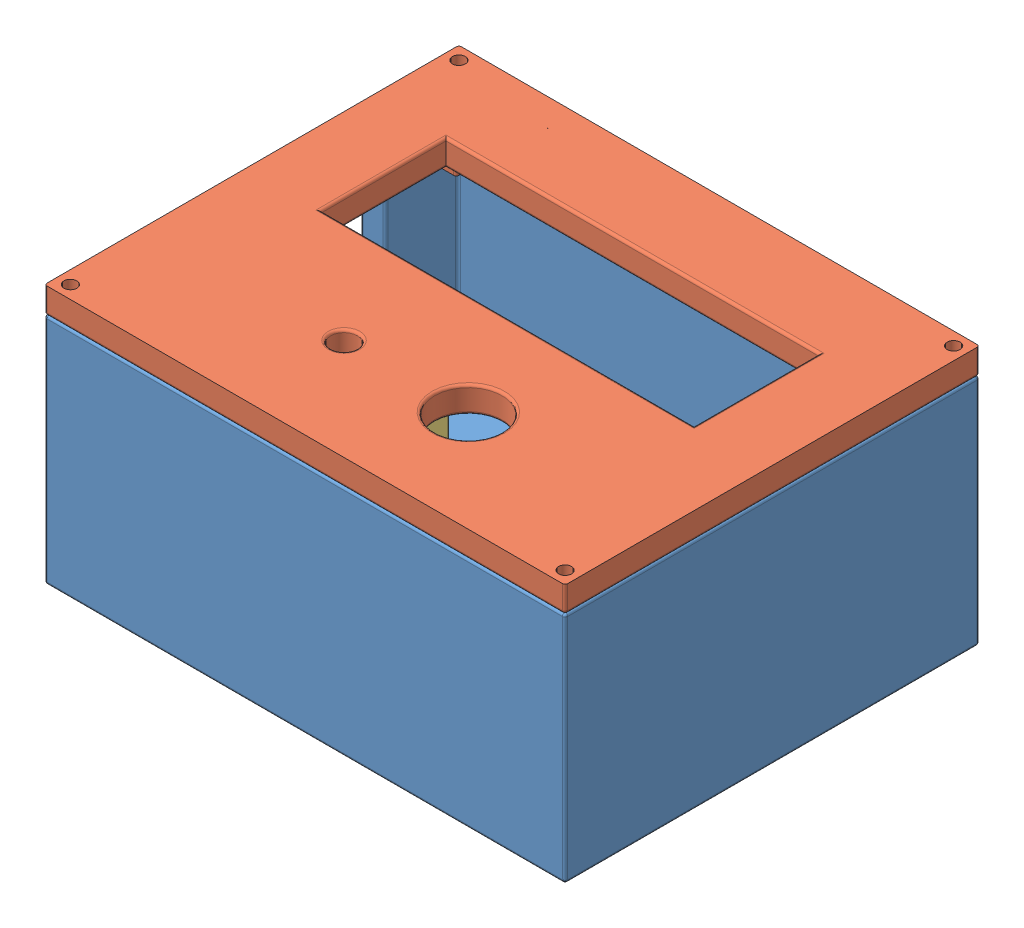
SolidWorks assembly Montagem, configuration Valor predeterminado. Lengths in mm.
Overall size (100.5 50 80).
3 component instances, 3 part files, 8 mates.
Components (placement in the parent):
- Principal-1: Principal [Valor predeterminado] at (-69.1888 -20.3417 0) size (100.5 45 80)
- Tampa-1: Tampa [Valor predeterminado] at (-69.1888 24.6583 0) x (1 0 0) z (0 1 0) size (100.5 80 8)
- Part1-1: Part1 [Valor predeterminado] at (-69.1888 24.6583 0) x (-1 0 0) z (0 -1 0) size (35 8 11)
Mates (geometry in assembly coordinates):
- InPlace1: in place: plane of Principal-1 through (-69.1888 19.6583 0) normal (0 1 0); plane of ? through (0 19.6583 0) normal (0 1 0); moOrthogonalPlaneRef_w of Principal-1 through (-69.1888 19.6583 0) normal (0 1 0); plane of ? through (0 19.6583 0) normal (0 0 -1); plane of Principal-1 through (-69.1888 19.6583 0) normal (0 1 0); plane of ? through (0 19.6583 0) normal (1 0 0); plane of Principal-1 through (-69.1888 24.6583 0) normal (0 1 0); unknown of Tampa-1
- Coincident1: coincident aligned: plane of Principal-1; plane of Tampa-1
- Coincident2: coincident aligned: moOrthogonalPlaneRef_w of Principal-1 through (-69.1888 24.6583 0) normal (0 0 -1); plane of Tampa-1 through (-69.1888 24.6583 0) normal (0 0 -1)
- Coincident3: coincident anti-aligned: moOrthogonalPlaneRef_w of Principal-1 through (-69.1888 24.6583 0) normal (-1 0 0); plane of Tampa-1 through (-69.1888 24.6583 0) normal (1 0 0)
- InPlace2: in place: plane of Tampa-1 through (-69.1888 24.6583 0) normal (0 -1 0); plane of ? through (0 24.6583 0) normal (0 -1 0); plane of Tampa-1 through (-69.1888 24.6583 0) normal (0 -1 0); plane of ? through (0 24.6583 0) normal (0 0 -1); plane of Tampa-1 through (-69.1888 24.6583 0) normal (0 -1 0); plane of ? through (0 24.6583 0) normal (-1 0 0); plane of Tampa-1 through (-69.1888 24.6583 0) normal (0 -1 0); unknown of Part1-1
- Coincident1: coincident aligned: plane of Tampa-1; plane of Part1-1
- Coincident2: coincident aligned: moOrthogonalPlaneRef_w of Tampa-1 through (-69.1888 24.6583 0) normal (0 0 -1); plane of Part1-1 through (-69.1888 24.6583 0) normal (0 0 -1)
- Coincident3: coincident anti-aligned: moOrthogonalPlaneRef_w of Tampa-1 through (-69.1888 24.6583 0) normal (1 0 0); plane of Part1-1 through (-69.1888 24.6583 0) normal (-1 0 0)
